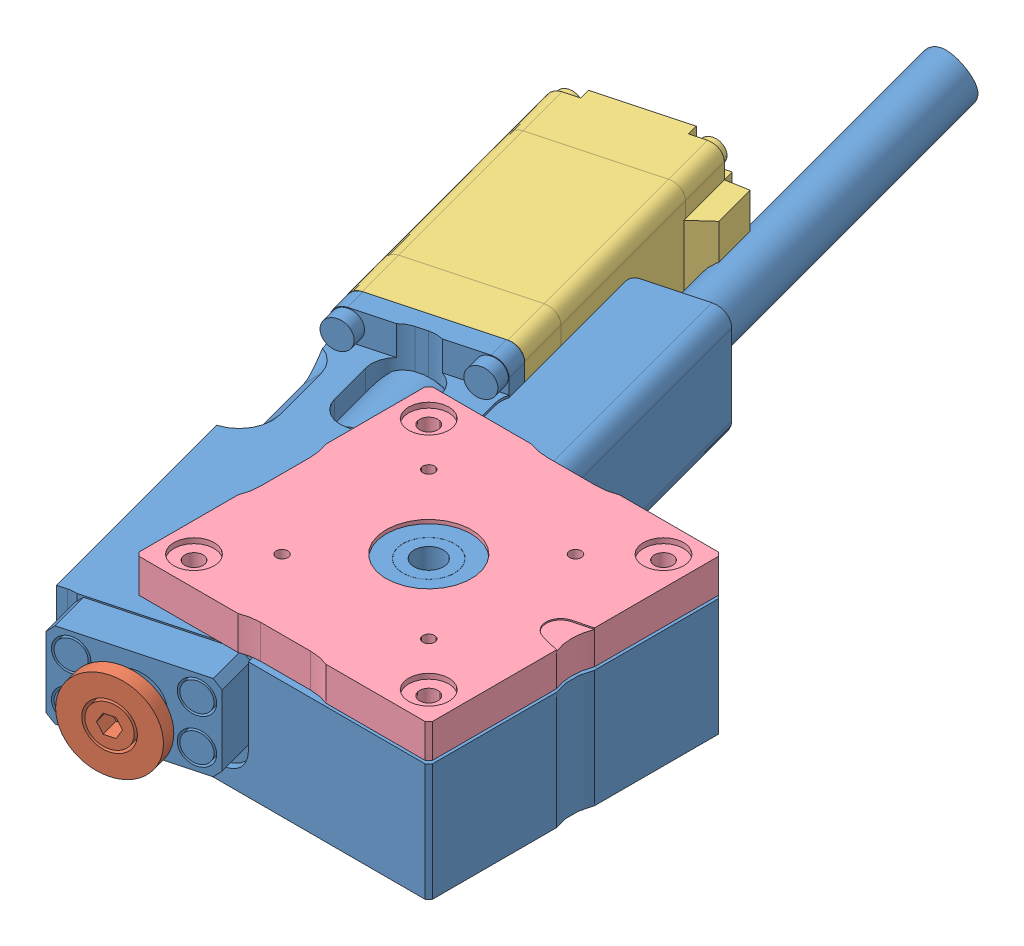
SolidWorks assembly RSM40, configuration RSM40x-T4A. Lengths in mm.
Overall size (68.74 21.5 138.27).
4 component instances, 4 part files, 12 mates.
Components (placement in the parent):
- RSM40_base^RSM40-1: RSM40_base^RSM40 [RSM40-T4] x (0 0 1) z (-1 0 0) size (134.69 21 58.39) (virtual)
- RSM40_knob^RSM40-1: RSM40_knob^RSM40 [Default] at (-13.7211 10.5 26.4526) x (-0.965926 0 0.258819) z (-0.258819 0 -0.965926) size (12 12 5) (virtual)
- NMS08_motor^RSM40-1: NMS08_motor^RSM40 [NMS08] at (-28.7326 10.5 -29.5711) x (0.965926 0 -0.258819) z (0.258819 0 0.965926) size (23 20 50) (virtual)
-  RSM40_top^RSM40-1:  RSM40_top^RSM40 [RSM40] x (0 0 1) z (-1 0 0) size (40 4.6 40) (virtual)
Mates (geometry in assembly coordinates):
- Coincident1: coincident anti-aligned: plane of RSM40_base^RSM40-1 through (5.694 0 21.2504) normal (0.258819 0 0.965926); plane of RSM40_knob^RSM40-1 through (-13.7211 10.5 26.4526) normal (-0.258819 0 -0.965926)
- Concentric1: concentric: cylinder of RSM40_base^RSM40-1 through (-13.9799 10.5 25.4867) axis (0.258819 0 0.965926) radius 3.75; point of RSM40_knob^RSM40-1
- Coincident3: coincident anti-aligned: plane of RSM40_base^RSM40-1 through (-19.0733 16.5 -32.1593) normal (-0.258819 0 -0.965926); plane of NMS08_motor^RSM40-1 through (-28.7326 10.5 -29.5711) normal (0.258819 0 0.965926)
- Parallel1: parallel aligned: plane of NMS08_motor^RSM40-1; plane of assembly through (0 0 0) normal (0 1 0)
- Concentric3: concentric: cylinder of RSM40_base^RSM40-1 through (-28.3444 10.5 -28.1222) axis (-0.258819 0 -0.965926) radius 7.5; point of NMS08_motor^RSM40-1
- Coincident8: coincident: unknown of ?
- Coincident9: coincident aligned: plane of  RSM40_top^RSM40-1; plane of assembly through (0 0 0) normal (0 1 0)
- Coincident10: coincident: unknown of ?
- Coincident11: coincident aligned: plane of RSM40_base^RSM40-1; plane of assembly through (0 0 0) normal (0 1 0)
- Coincident12: coincident anti-aligned: plane of RSM40_base^RSM40-1 through (0 0 0) normal (-1 0 0); plane of assembly through (0 0 0) normal (1 0 0)
- GearMate2: gear = 60 : 1 mm: cylinder of RSM40_knob^RSM40-1 through (-13.7211 10.5 26.4526) axis (-0.258819 0 -0.965926) radius 6; cylinder of  RSM40_top^RSM40-1 through (0 16.9 0) axis (0 1 0) radius 5.8
- Home Position: coincident aligned: plane of  RSM40_top^RSM40-1 through (0 0 0) normal (1 0 0); plane of RSM40_base^RSM40-1 through (0 0 0) normal (0 0 1)
